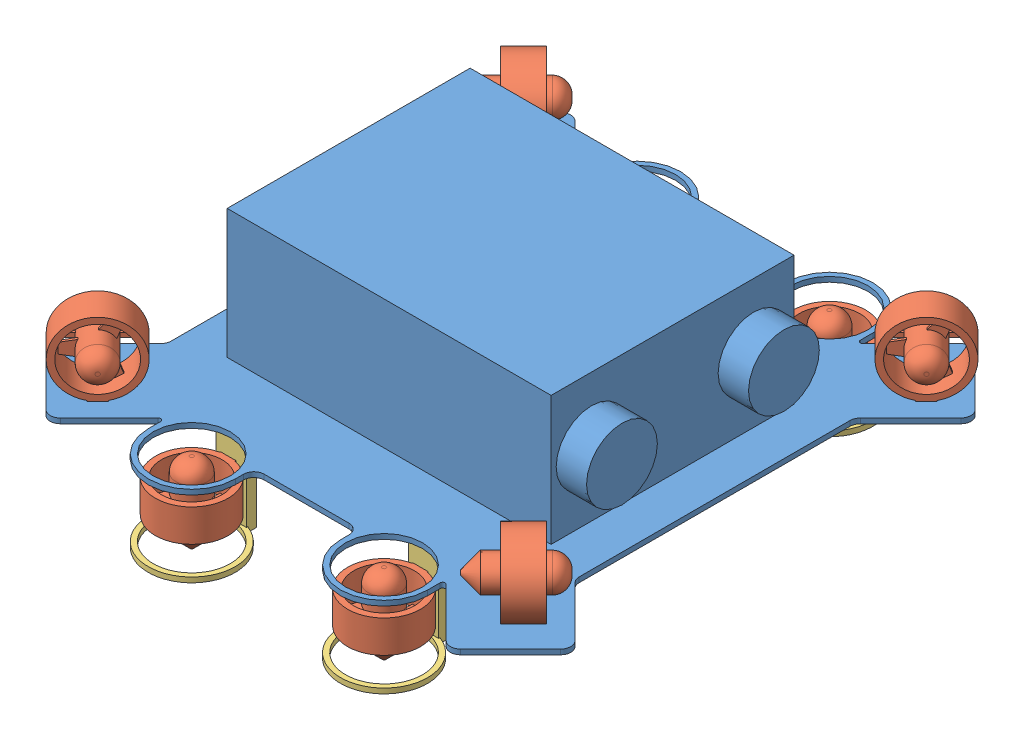
SolidWorks assembly Visual, configuration Default. Lengths in mm.
Overall size (658.44 263.53 668.02).
13 component instances, 3 part files, 36 mates.
Components (placement in the parent):
- VisualBase-1: VisualBase [Default] at (190.7305 225.3417 496.8084) x (1 0 0) z (0 -1 0) size (653.22 668.02 168.28)
- VisualThruster-1: VisualThruster [Default] at (452.9971 271.0617 742.9106) x (0.707107 0 0.707107) z (0 1 0) size (91.44 99.06 91.44)
- VisualThruster-2: VisualThruster [Default] at (-63.1439 271.0617 226.7696) x (0.707107 0 0.707107) z (0 1 0) size (91.44 99.06 91.44)
- VisualThruster-3: VisualThruster [Default] at (311.3805 179.6217 217.4084) x (-1 0 0) z (0 0 -1) size (91.44 99.06 91.44)
- VisualThruster-4: VisualThruster [Default] at (70.0805 179.6217 776.2084) size (91.44 99.06 91.44)
- VisualThruster-5: VisualThruster [Default] at (311.3805 179.6217 776.2084) size (91.44 99.06 91.44)
- VisualThruster-6: VisualThruster [Default] at (459.7009 271.0617 244.0024) x (-0.707107 0 0.707107) z (0 1 0) size (91.44 99.06 91.44)
- VisualThruster-7: VisualThruster [Default] at (-60.2416 271.0617 763.9449) x (-0.707107 0 0.707107) z (0 1 0) size (91.44 99.06 91.44)
- VisualThruster-8: VisualThruster [Default] at (70.0805 179.6217 217.4084) x (-1 0 0) z (0 0 -1) size (91.44 99.06 91.44)
- VerticalThrusterMount-1: VerticalThrusterMount [Default] at (311.3805 123.7417 266.9384) x (1 0 0) z (0 1 0) size (109.22 116.84 95.25)
- VerticalThrusterMount-2: VerticalThrusterMount [Default] at (70.0805 123.7417 266.9384) x (1 0 0) z (0 1 0) size (109.22 116.84 95.25)
- VerticalThrusterMount-3: VerticalThrusterMount [Default] at (311.3805 123.7417 726.6784) x (-1 0 0) z (0 1 0) size (109.22 116.84 95.25)
- VerticalThrusterMount-4: VerticalThrusterMount [Default] at (70.0805 123.7417 726.6784) x (-1 0 0) z (0 1 0) size (109.22 116.84 95.25)
Mates (geometry in assembly coordinates):
- Coincident1: coincident aligned: plane of VisualThruster-1 through (452.9971 225.3417 742.9106) normal (0 -1 0); plane of VisualThruster-2 through (-63.1439 225.3417 226.7696) normal (0 -1 0)
- Coincident3: coincident aligned: plane of VisualThruster-2 through (-63.1439 225.3417 226.7696) normal (0 -1 0); plane of VisualThruster-6 through (459.7009 225.3417 244.0024) normal (0 -1 0)
- Coincident4: coincident aligned: plane of VisualThruster-2 through (-63.1439 225.3417 226.7696) normal (0 -1 0); plane of VisualThruster-7 through (-60.2416 225.3417 763.9449) normal (0 -1 0)
- Coincident5: coincident anti-aligned: plane of VisualBase-1 through (459.5128 225.3417 326.8089) normal (0 1 0); plane of VisualThruster-1 through (452.9971 225.3417 742.9106) normal (0 -1 0)
- Parallel1: parallel: plane of VisualBase-1 through (513.6186 218.9917 756.8347) normal (0.707107 0 0.707107); line of VisualThruster-1 through (431.8935 225.3417 750.5438) axis (0.707107 0 -0.707107)
- Parallel2: parallel aligned: plane of VisualBase-1 through (-69.2959 218.9917 819.6965) normal (-0.707107 0 0.707107); plane of VisualThruster-7 through (-52.6084 228.5167 785.0485) normal (-0.707107 0 0.707107)
- Parallel3: parallel: line of VisualBase-1 through (-132.1577 225.3417 236.782) axis (0.707107 0 -0.707107); plane of VisualThruster-2 through (-55.5106 228.5167 205.666) normal (-0.707107 0 -0.707107)
- Parallel5: parallel aligned: plane of VisualBase-1 through (450.7568 218.9917 173.9202) normal (0.707107 0 -0.707107); plane of VisualThruster-6 through (480.8045 228.5167 251.6356) normal (0.707107 0 -0.707107)
- Concentric1: concentric anti-aligned: circle of VisualBase-1; cylinder of VisualThruster-5 through (311.3805 159.3017 776.2084) axis (0 1 0) radius 45.72
- Concentric2: concentric aligned: cylinder of VisualBase-1 through (70.0805 63.4167 776.2084) axis (0 1 0) radius 48.26; cylinder of VisualThruster-4 through (70.0805 159.3017 776.2084) axis (0 1 0) radius 45.72
- Concentric3: concentric aligned: circle of VisualBase-1; cylinder of VisualThruster-3 through (311.3805 159.3017 217.4084) axis (0 1 0) radius 45.72
- Concentric4: concentric aligned: circle of VisualBase-1; cylinder of VisualThruster-8 through (70.0805 159.3017 217.4084) axis (0 1 0) radius 45.72
- Coincident12: coincident aligned: plane of VisualThruster-3 through (311.3805 179.6217 263.1284) normal (0 0 1); plane of VisualThruster-8 through (70.0805 179.6217 263.1284) normal (0 0 1)
- Parallel6: parallel anti-aligned: plane of VisualBase-1 through (137.3905 218.9917 240.7261) normal (0 0 -1); plane of VisualThruster-3 through (311.3805 179.6217 263.1284) normal (0 0 1)
- Parallel7: parallel anti-aligned: plane of VisualBase-1 through (393.9305 387.2667 649.2084) normal (0 0 1); plane of VisualThruster-4 through (70.0805 179.6217 730.4884) normal (0 0 -1)
- Parallel8: parallel anti-aligned: plane of VisualBase-1 through (393.9305 387.2667 649.2084) normal (0 0 1); plane of VisualThruster-5 through (311.3805 179.6217 730.4884) normal (0 0 -1)
- Coincident16: coincident aligned: plane of VisualThruster-4 through (70.0805 199.9417 776.2084) normal (0 1 0); plane of VisualThruster-5 through (311.3805 199.9417 776.2084) normal (0 1 0)
- Coincident17: coincident aligned: plane of VisualThruster-5 through (311.3805 199.9417 776.2084) normal (0 1 0); plane of VisualThruster-8 through (70.0805 199.9417 217.4084) normal (0 1 0)
- Coincident18: coincident aligned: plane of VisualThruster-3 through (311.3805 199.9417 217.4084) normal (0 1 0); plane of VisualThruster-8 through (70.0805 199.9417 217.4084) normal (0 1 0)
- Distance1: distance = 25.4 mm aligned: plane of VisualThruster-4 through (70.0805 199.9417 776.2084) normal (0 1 0); plane of VisualBase-1 through (459.5128 225.3417 326.8089) normal (0 1 0)
- Coincident20: coincident aligned: plane of VerticalThrusterMount-3 through (311.3805 123.7417 726.6784) normal (0 -1 0); plane of VerticalThrusterMount-4 through (70.0805 123.7417 726.6784) normal (0 -1 0)
- Coincident21: coincident aligned: plane of VerticalThrusterMount-2 through (70.0805 123.7417 266.9384) normal (0 -1 0); plane of VerticalThrusterMount-3 through (311.3805 123.7417 726.6784) normal (0 -1 0)
- Coincident22: coincident aligned: plane of VerticalThrusterMount-1 through (311.3805 123.7417 266.9384) normal (0 -1 0); plane of VerticalThrusterMount-2 through (70.0805 123.7417 266.9384) normal (0 -1 0)
- Coincident23: coincident anti-aligned: plane of VisualBase-1 through (459.5128 218.9917 326.8089) normal (0 -1 0); plane of VerticalThrusterMount-1 through (311.3805 218.9917 266.9384) normal (0 1 0)
- Parallel11: parallel anti-aligned: plane of VisualBase-1 through (393.9305 387.2667 344.4084) normal (0 0 -1); plane of VerticalThrusterMount-1 through (292.3305 218.9917 279.6384) normal (0 0 1)
- Parallel10: parallel aligned: plane of VisualBase-1 through (393.9305 387.2667 344.4084) normal (0 0 -1); plane of VerticalThrusterMount-2 through (51.0305 218.9917 266.9384) normal (0 0 -1)
- Coincident26: coincident anti-aligned: cylinder of VisualBase-1 through (311.3805 218.9917 217.4084) axis (0 1 0) radius 54.61; circle of VerticalThrusterMount-1
- Concentric7: concentric anti-aligned: cylinder of VisualBase-1 through (70.0805 218.9917 217.4084) axis (0 1 0) radius 54.61; cylinder of VerticalThrusterMount-2 through (70.0805 130.0917 217.4084) axis (0 -1 0) radius 54.61
- Parallel13: parallel aligned: plane of VisualBase-1 through (393.9305 387.2667 649.2084) normal (0 0 1); plane of VerticalThrusterMount-3 through (330.4305 218.9917 726.6784) normal (0 0 1)
- Coincident28: coincident aligned: plane of VerticalThrusterMount-3 through (330.4305 218.9917 726.6784) normal (0 0 1); plane of VerticalThrusterMount-4 through (89.1305 218.9917 726.6784) normal (0 0 1)
- Concentric8: concentric aligned: circle of VisualBase-1; circle of VerticalThrusterMount-4
- Concentric9: concentric aligned: circle of VisualBase-1; circle of VerticalThrusterMount-3
- Distance3: distance = 25.4 mm aligned: plane of VisualThruster-1 through (467.3655 271.0617 728.5422) normal (0.707107 0 -0.707107); plane of VisualBase-1 through (450.5325 218.9917 675.7881) normal (0.707107 0 -0.707107)
- Distance4: distance = 25.4 mm aligned: plane of VisualThruster-6 through (474.0693 271.0617 258.3708) normal (0.707107 0 0.707107); plane of VisualBase-1 through (513.6186 218.9917 254.7425) normal (0.707107 0 0.707107)
- Distance5: distance = 25.4 mm aligned: plane of VisualThruster-2 through (-48.7755 271.0617 212.4012) normal (0.707107 0 -0.707107); plane of VisualBase-1 through (-51.3354 218.9917 173.9202) normal (0.707107 0 -0.707107)
- Distance6: distance = 25.4 mm aligned: plane of VisualThruster-7 through (-45.8732 271.0617 778.3133) normal (0.707107 0 0.707107); plane of VisualBase-1 through (10.0504 218.9917 758.3107) normal (0.707107 0 0.707107)
